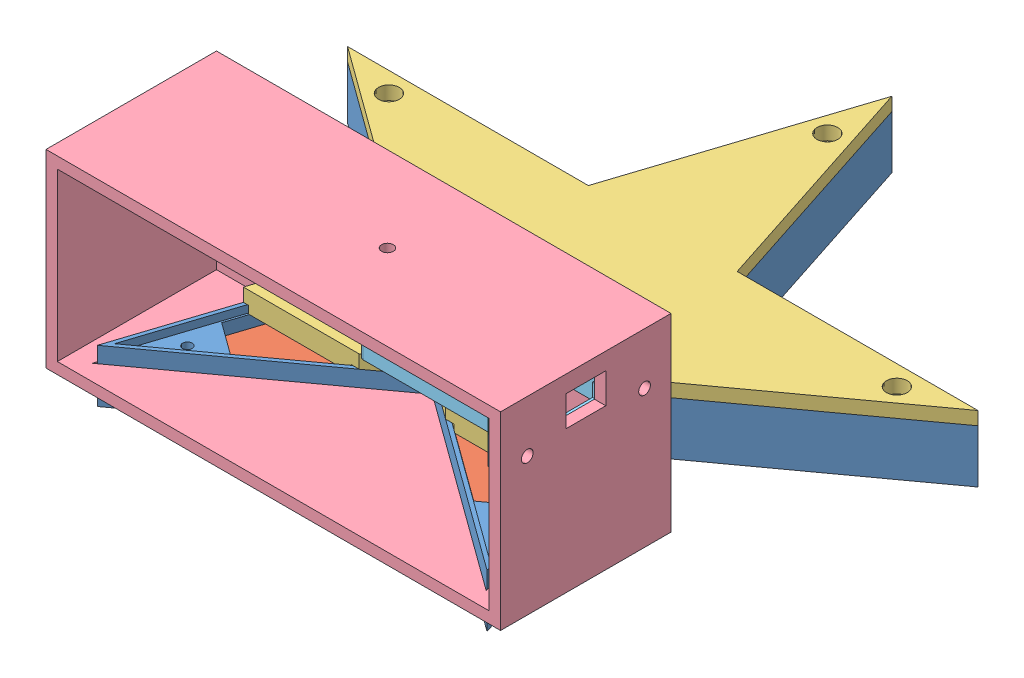
SolidWorks assembly Ensamblaje1, configuration Default. Lengths in mm.
Overall size (175 57 175).
7 component instances, 6 part files, 11 mates.
Components (placement in the parent):
- Base estrella-1: Base estrella [Predeterminado] at (24.2364 168.75 16.779) size (175 14 175)
- Soportes led^Ensamblaje1-1: Soportes led^Ensamblaje1 [Predeterminado] at (24.2364 171.75 16.779) x (1 0 0) z (0 1 0) size (123.07 117.05 3) (virtual)
- Tapa trasera-1: Tapa trasera [Predeterminado] at (24.2364 180.75 16.779) x (1 0 0) z (0 1 0) size (166.43 129.21 5.5)
- Pieza1-1: Pieza1 [Predeterminado] at (24.2364 168.75 16.779) x (-1 0 0) z (0 -1 0) size (120 45 50)
- Ensamblaje Caja Arduino_v2-1: Ensamblaje Caja Arduino_v2 [Default] at (60.0864 208.45 70.0332) size (53.37 14.3 38.93)
  - Base Arduino Nano_v2-1: Base Arduino Nano_v2 [Default] at origin size (53.37 9.8 38.93)
  - Tapa arduino Nano_v2-1: Tapa arduino Nano_v2 [Predeterminado] at (0 7.3 0) x (1 0 0) z (0 1 0) size (53.37 38.93 7)
Mates (geometry in assembly coordinates):
- EnPosición1: in place: plane of Base estrella-1 through (24.2364 170.25 16.779) normal (0 1 0); plane of ? through (0 170.25 0) normal (0 1 0); moOrthogonalPlaneRef_w of Base estrella-1 through (24.2364 170.25 16.779) normal (0 1 0); plane of ? through (0 170.25 0) normal (0 0 -1); plane of Base estrella-1 through (24.2364 170.25 16.779) normal (0 1 0); plane of ? through (0 170.25 0) normal (1 0 0); plane of Base estrella-1 through (24.2364 171.75 16.779) normal (0 1 0); unknown of Soportes led^Ensamblaje1-1
- Coincidente1: coincident aligned: plane of Base estrella-1; plane of Soportes led^Ensamblaje1-1
- Coincidente2: coincident aligned: moOrthogonalPlaneRef_w of Base estrella-1 through (24.2364 171.75 16.779) normal (0 0 -1); plane of Soportes led^Ensamblaje1-1 through (24.2364 171.75 16.779) normal (0 0 -1)
- Coincidente3: coincident anti-aligned: moOrthogonalPlaneRef_w of Base estrella-1 through (24.2364 171.75 16.779) normal (-1 0 0); plane of Soportes led^Ensamblaje1-1 through (24.2364 171.75 16.779) normal (1 0 0)
- EnPosición3: in place: plane of Base estrella-1 through (24.2364 168.75 16.779) normal (0 -1 0); plane of ? through (0 168.75 0) normal (0 -1 0); plane of Base estrella-1 through (24.2364 168.75 16.779) normal (0 -1 0); plane of ? through (0 168.75 0) normal (0 0 -1); plane of Base estrella-1 through (24.2364 168.75 16.779) normal (0 -1 0); plane of ? through (0 168.75 0) normal (-1 0 0); plane of Base estrella-1 through (24.2364 168.75 16.779) normal (0 -1 0); unknown of Pieza1-1
- Coincidente1: coincident aligned: plane of Base estrella-1; plane of Pieza1-1
- Coincidente2: coincident aligned: moOrthogonalPlaneRef_w of Base estrella-1 through (24.2364 168.75 16.779) normal (0 0 -1); plane of Pieza1-1 through (24.2364 168.75 16.779) normal (0 0 -1)
- Coincidente3: coincident anti-aligned: moOrthogonalPlaneRef_w of Base estrella-1 through (24.2364 168.75 16.779) normal (1 0 0); plane of Pieza1-1 through (24.2364 168.75 16.779) normal (-1 0 0)
- Coincidente1: coincident anti-aligned: plane of Pieza1-1 through (24.2364 222.75 16.779) normal (0 -1 0); plane of Ensamblaje Caja Arduino_v2-1/Tapa arduino Nano_v2-1 through (78.2364 222.75 51.568) normal (0 1 0)
- Coincidente2: coincident anti-aligned: plane of Pieza1-1 through (81.2364 175.75 92.568) normal (-1 0 0); plane of Ensamblaje Caja Arduino_v2-1/Tapa arduino Nano_v2-1 through (81.2364 221.25 89.4984) normal (1 0 0)
- Coincidente3: coincident anti-aligned: plane of Pieza1-1 through (84.2364 175.75 50.568) normal (0 0 1); plane of Ensamblaje Caja Arduino_v2-1/Base Arduino Nano_v2-1 through (77.2364 215.75 50.568) normal (0 0 -1)
